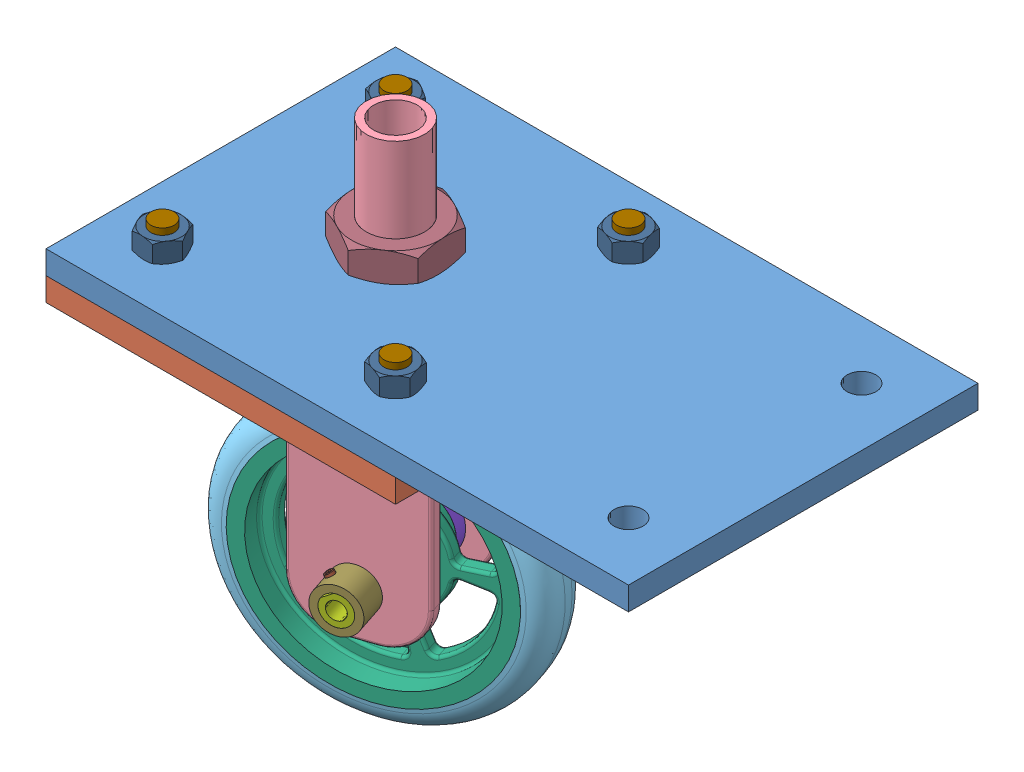
SolidWorks assembly Final Assembly - Caster, configuration Default. Lengths in mm.
Overall size (209.59 196.65 120).
23 component instances, 13 part files, 42 mates.
Components (placement in the parent):
- Part 1 - Base-1: Part 1 - Base [Default] at (34.3466 79.384 167.9379) size (200 8 120)
- Part 2 - Mount-1: Part 2 - Mount [Default] at (34.3466 71.384 167.9379) size (120 8 120)
- Bearing-1: Bearing [Default] at (34.3466 71.384 167.9379) x (0.90375 0 -0.42806) z (0 -1 0) size (30 30 5)
- Part 3 - Fork-3: Part 3 - Fork [Default] at (34.3466 66.384 167.9379) x (0.949371 0 -0.314156) z (-0.314156 0 -0.949371) size (80 143 80)
- Sub-Assembly - Wheel and Axle-1: Sub-Assembly - Wheel and Axle [Default] at (93.1896 48.8704 110.4922) x (0.314156 0 0.949371) z (-0.494931 -0.853358 0.163778) size (60 109.56 109.56)
  - Part 4 - Tire-1: Part 4 - Tire [Default] at (36.0514 37.5977 82.131) size (20 96.05 96.05)
  - Part 5 - Wheel-1: Part 5 - Wheel [Default] at (36.0514 37.5977 82.131) x (1 0 0) z (0 -0.50832 0.861168) size (20 80 80)
  - Axle.SLDPART-1: Axle.SLDPART [Default] at (36.0514 37.5977 82.131) x (0 0.423529 0.905883) z (-1 0 0) size (10 10 60)
- Washer-1: Washer [Default] at (30.2648 -1.616 158.7553) x (-0.93685 -0.161875 0.310013) z (-0.314156 0 -0.949371) size (25 25 5)
- Washer-2: Washer [Default] at (38.1187 -1.616 182.4896) x (-0.949371 0 0.314156) z (-0.314156 0 -0.949371) size (25 25 5)
- hex screw_am-1: hex screw_am [B18.6.7M - M8 x 1.25 x 25 Indented HHMS --25N] at (74.3466 65.384 127.9379) x (0 1 0) z (-0.223088 0 0.974798) size (31 15.01 13)
- hex screw_am-2: hex screw_am [B18.6.7M - M8 x 1.25 x 25 Indented HHMS --25N] at (-5.6534 65.384 127.9379) x (0 1 0) z (-0.28415 0 0.95878) size (31 15.01 13)
- hex screw_am-3: hex screw_am [B18.6.7M - M8 x 1.25 x 25 Indented HHMS --25N] at (-5.6534 65.384 207.9379) x (0 1 0) z (0.576705 0 0.816952) size (31 15.01 13)
- hex screw_am-4: hex screw_am [B18.6.7M - M8 x 1.25 x 25 Indented HHMS --25N] at (74.3466 65.384 207.9379) x (0 1 0) z (-0.76604 0 0.642793) size (31 15.01 13)
- hex nut style 1_am-1: hex nut style 1_am [B18.2.4.1M - Hex nut, Style 1,  M8 x 1.25 --D-N] at (-5.6534 94.184 127.9379) x (1 0 0) z (0 1 0) size (13 15.01 6.8)
- hex nut style 1_am-2: hex nut style 1_am [B18.2.4.1M - Hex nut, Style 1,  M8 x 1.25 --D-N] at (-5.6534 94.184 207.9379) x (-0.073543 0 0.997292) z (0 1 0) size (13 15.01 6.8)
- hex nut style 1_am-3: hex nut style 1_am [B18.2.4.1M - Hex nut, Style 1,  M8 x 1.25 --D-N] at (74.3466 94.184 207.9379) x (0.972665 0 -0.232211) z (0 1 0) size (13 15.01 6.8)
- hex nut style 1_am-4: hex nut style 1_am [B18.2.4.1M - Hex nut, Style 1,  M8 x 1.25 --D-N] at (74.3466 94.184 127.9379) x (0.974359 0 -0.224998) z (0 1 0) size (13 15.01 6.8)
- socket set screw flat point_am-2: socket set screw flat point_am [B18.3.6M - M3 x 0.5 x 4 Hex Socket Flat Pt. SS --N] at (21.096 5.4703 145.9895) x (0.524287 -0.833681 -0.173492) z (0.018341 -0.192635 0.981099) size (4 3 3)
- collar-1: collar [Default] at (25.5524 -1.616 144.5148) x (0.791473 0.552246 -0.261906) z (0.314156 0 0.949371) size (15 15 10)
- collar-2: collar [Default] at (41.2602 -1.616 191.9833) x (0.791473 0.552246 -0.261906) z (0.314156 0 0.949371) size (15 15 10)
- socket set screw flat point_am-3: socket set screw flat point_am [B18.3.6M - M3 x 0.5 x 4 Hex Socket Flat Pt. SS --N] at (36.8038 5.4703 193.458) x (0.524287 -0.833681 -0.173492) z (0.01526 -0.194507 0.980782) size (4 3 3)
- hex nut jam_am-2: hex nut jam_am [B18.2.4.5M - Hex jam nut,  M20 x 2.5 --D-N] at (34.3466 97.384 167.9379) x (0.998141 0 -0.060942) z (0 1 0) size (30 34.64 10)
Mates (geometry in assembly coordinates):
- Coincident1: coincident: circle of Part 1 - Base-1; circle of Part 2 - Mount-1
- Concentric1: concentric: cylinder of Part 1 - Base-1 through (-5.6534 79.384 207.9379) axis (0 1 0) radius 5; cylinder of Part 2 - Mount-1 through (-5.6534 69.384 207.9379) axis (0 1 0) radius 5
- Concentric5: concentric: circle of Part 2 - Mount-1; circle of Bearing-1
- Concentric6: concentric: circle of Part 2 - Mount-1; circle of Bearing-1
- Concentric8: concentric: circle of Part 2 - Mount-1; circle of Bearing-1
- Concentric10: concentric: cylinder of Part 2 - Mount-1 through (34.3466 71.384 167.9379) axis (0 1 0) radius 12.5; cylinder of Bearing-1 through (34.3466 66.384 167.9379) axis (0 1 0) radius 15
- Concentric11: concentric: circle of Part 2 - Mount-1; circle of Bearing-1
- Concentric15: concentric: circle of Bearing-1; circle of Part 3 - Fork-3
- Coincident3: coincident: plane of Part 2 - Mount-1 through (34.3466 71.384 167.9379) normal (0 -1 0); plane of Bearing-1 through (34.3466 71.384 167.9379) normal (0 1 0)
- Coincident4: coincident: plane of Bearing-1 through (34.3466 66.384 167.9379) normal (0 -1 0); plane of Part 3 - Fork-3 through (34.3466 66.384 167.9379) normal (0 1 0)
- Concentric16: concentric: cylinder of Part 3 - Fork-3 through (24.6099 -1.616 141.6667) axis (0.314156 0 0.949371) radius 5; cylinder of Sub-Assembly - Wheel and Axle-1/Axle.SLDPART-1 through (23.9816 -1.616 139.7679) axis (0.314156 0 0.949371) radius 5
- Concentric17: concentric: cylinder of Sub-Assembly - Wheel and Axle-1/Axle.SLDPART-1 through (23.9816 -1.616 139.7679) axis (0.314156 0 0.949371) radius 5; cylinder of Washer-1 through (30.2648 -1.616 158.7553) axis (-0.314156 0 -0.949371) radius 5
- Coincident5: coincident: plane of Sub-Assembly - Wheel and Axle-1/Part 5 - Wheel-1 through (35.0111 -1.6919 157.1847) normal (-0.314156 0 -0.949371); plane of Washer-1 through (30.2648 -1.616 158.7553) normal (0.314156 0 0.949371)
- Coincident6: coincident: plane of Part 3 - Fork-3 through (48.6216 -16.616 147.4142) normal (0.314156 0 0.949371); plane of Washer-1 through (28.694 -1.616 154.0085) normal (-0.314156 0 -0.949371)
- Concentric18: concentric: cylinder of Sub-Assembly - Wheel and Axle-1/Axle.SLDPART-1 through (23.9816 -1.616 139.7679) axis (0.314156 0 0.949371) radius 5; cylinder of Washer-2 through (38.1187 -1.616 182.4896) axis (-0.314156 0 -0.949371) radius 5
- Coincident8: coincident: plane of Sub-Assembly - Wheel and Axle-1/Part 5 - Wheel-1 through (41.2942 -1.6919 176.1722) normal (0.314156 0 0.949371); plane of Washer-2 through (36.5479 -1.616 177.7428) normal (-0.314156 0 -0.949371)
- Concentric21: concentric: cylinder of Part 2 - Mount-1 through (74.3466 69.384 127.9379) axis (0 1 0) radius 5; cylinder of hex screw_am-1 through (74.3466 39.984 127.9379) axis (0 -1 0) radius 4
- Coincident11: coincident: plane of Part 2 - Mount-1 through (34.3466 71.384 167.9379) normal (0 -1 0); plane of hex screw_am-1 through (70.4474 71.384 127.0456) normal (0 1 0)
- Concentric22: concentric: cylinder of Part 2 - Mount-1 through (-5.6534 69.384 127.9379) axis (0 1 0) radius 5; cylinder of hex screw_am-2 through (-5.6534 39.984 127.9379) axis (0 -1 0) radius 4
- Coincident12: coincident: plane of Part 2 - Mount-1 through (34.3466 71.384 167.9379) normal (0 -1 0); plane of hex screw_am-2 through (-9.4886 71.384 126.8013) normal (0 1 0)
- Concentric23: concentric: cylinder of Part 2 - Mount-1 through (-5.6534 69.384 207.9379) axis (0 1 0) radius 5; cylinder of hex screw_am-3 through (-5.6534 39.984 207.9379) axis (0 -1 0) radius 4
- Coincident13: coincident: plane of Part 2 - Mount-1 through (34.3466 71.384 167.9379) normal (0 -1 0); plane of hex screw_am-3 through (-8.9213 71.384 210.2447) normal (0 1 0)
- Concentric24: concentric: cylinder of Part 2 - Mount-1 through (74.3466 69.384 207.9379) axis (0 1 0) radius 5; cylinder of hex screw_am-4 through (74.3466 39.984 207.9379) axis (0 -1 0) radius 4
- Coincident14: coincident: plane of Part 2 - Mount-1 through (34.3466 71.384 167.9379) normal (0 -1 0); plane of hex screw_am-4 through (71.7754 71.384 204.8738) normal (0 1 0)
- Concentric25: concentric: cylinder of hex screw_am-2 through (-5.6534 39.984 127.9379) axis (0 -1 0) radius 4; cylinder of hex nut style 1_am-1 through (-5.6534 87.384 127.9379) axis (0 1 0) radius 3.4
- Coincident15: coincident: plane of Part 1 - Base-1 through (34.3466 87.384 167.9379) normal (0 1 0); plane of hex nut style 1_am-1 through (-5.6534 87.384 120.4324) normal (0 -1 0)
- Concentric26: concentric: cylinder of hex screw_am-3 through (-5.6534 39.984 207.9379) axis (0 -1 0) radius 4; cylinder of hex nut style 1_am-2 through (-5.6534 87.384 207.9379) axis (0 1 0) radius 3.4
- Coincident16: coincident: plane of Part 1 - Base-1 through (34.3466 87.384 167.9379) normal (0 1 0); plane of hex nut style 1_am-2 through (1.8318 87.384 208.4899) normal (0 -1 0)
- Concentric27: concentric: cylinder of hex screw_am-4 through (74.3466 39.984 207.9379) axis (0 -1 0) radius 4; cylinder of hex nut style 1_am-3 through (74.3466 87.384 207.9379) axis (0 1 0) radius 3.4
- Coincident17: coincident: plane of Part 1 - Base-1 through (34.3466 87.384 167.9379) normal (0 1 0); plane of hex nut style 1_am-3 through (72.6037 87.384 200.6375) normal (0 -1 0)
- Concentric28: concentric: cylinder of hex screw_am-1 through (74.3466 39.984 127.9379) axis (0 -1 0) radius 4; cylinder of hex nut style 1_am-4 through (74.3466 87.384 127.9379) axis (0 1 0) radius 3.4
- Coincident18: coincident: plane of Part 1 - Base-1 through (34.3466 87.384 167.9379) normal (0 1 0); plane of hex nut style 1_am-4 through (72.6578 87.384 120.6248) normal (0 -1 0)
- Coincident21: coincident: plane of Sub-Assembly - Wheel and Axle-1/Axle.SLDPART-1 through (23.0389 0.9319 150.6132) normal (-0.524287 0.833681 0.173492); plane of socket set screw flat point_am-2 through (24.0445 2.6531 145.3812) normal (0.524287 -0.833681 -0.173492)
- Concentric30: concentric: cylinder of Sub-Assembly - Wheel and Axle-1/Axle.SLDPART-1 through (23.9816 -1.616 139.7679) axis (0.314156 0 0.949371) radius 5; cylinder of collar-1 through (27.1232 -1.616 149.2616) axis (-0.314156 0 -0.949371) radius 5
- Coincident23: coincident: plane of Part 3 - Fork-3 through (47.0508 -16.616 142.6674) normal (-0.314156 0 -0.949371); plane of collar-1 through (27.1232 -1.616 149.2616) normal (0.314156 0 0.949371)
- Concentric31: concentric: cylinder of socket set screw flat point_am-2 through (14.4375 16.058 148.1928) axis (-0.524287 0.833681 0.173492) radius 1.5; cylinder of collar-1 through (20.8338 5.8871 146.0762) axis (0.524287 -0.833681 -0.173492) radius 1.5
- Concentric32: concentric: cylinder of Sub-Assembly - Wheel and Axle-1/Axle.SLDPART-1 through (23.9816 -1.616 139.7679) axis (0.314156 0 0.949371) radius 5; cylinder of collar-2 through (42.831 -1.616 196.7302) axis (-0.314156 0 -0.949371) radius 5
- Coincident24: coincident: plane of Part 3 - Fork-3 through (59.6171 -16.616 180.6422) normal (0.314156 0 0.949371); plane of collar-2 through (39.6894 -1.616 187.2365) normal (-0.314156 0 -0.949371)
- Concentric33: concentric: cylinder of collar-2 through (36.5416 5.8871 193.5448) axis (0.524287 -0.833681 -0.173492) radius 1.5; cylinder of socket set screw flat point_am-3 through (30.1454 16.058 195.6614) axis (-0.524287 0.833681 0.173492) radius 1.5
- Coincident25: coincident: plane of Sub-Assembly - Wheel and Axle-1/Axle.SLDPART-1 through (35.6052 0.9319 188.588) normal (-0.524287 0.833681 0.173492); plane of socket set screw flat point_am-3 through (39.7523 2.6524 192.8533) normal (0.524287 -0.833681 -0.173492)
- Concentric41: concentric: cylinder of Part 3 - Fork-3 through (34.3466 126.384 167.9379) axis (0 -1 0) radius 10; cylinder of hex nut jam_am-2 through (34.3466 87.384 167.9379) axis (0 1 0) radius 8.75
- Coincident26: coincident: plane of Part 1 - Base-1 through (34.3466 87.384 167.9379) normal (0 1 0); plane of hex nut jam_am-2 through (4.4023 87.384 169.7662) normal (0 -1 0)
